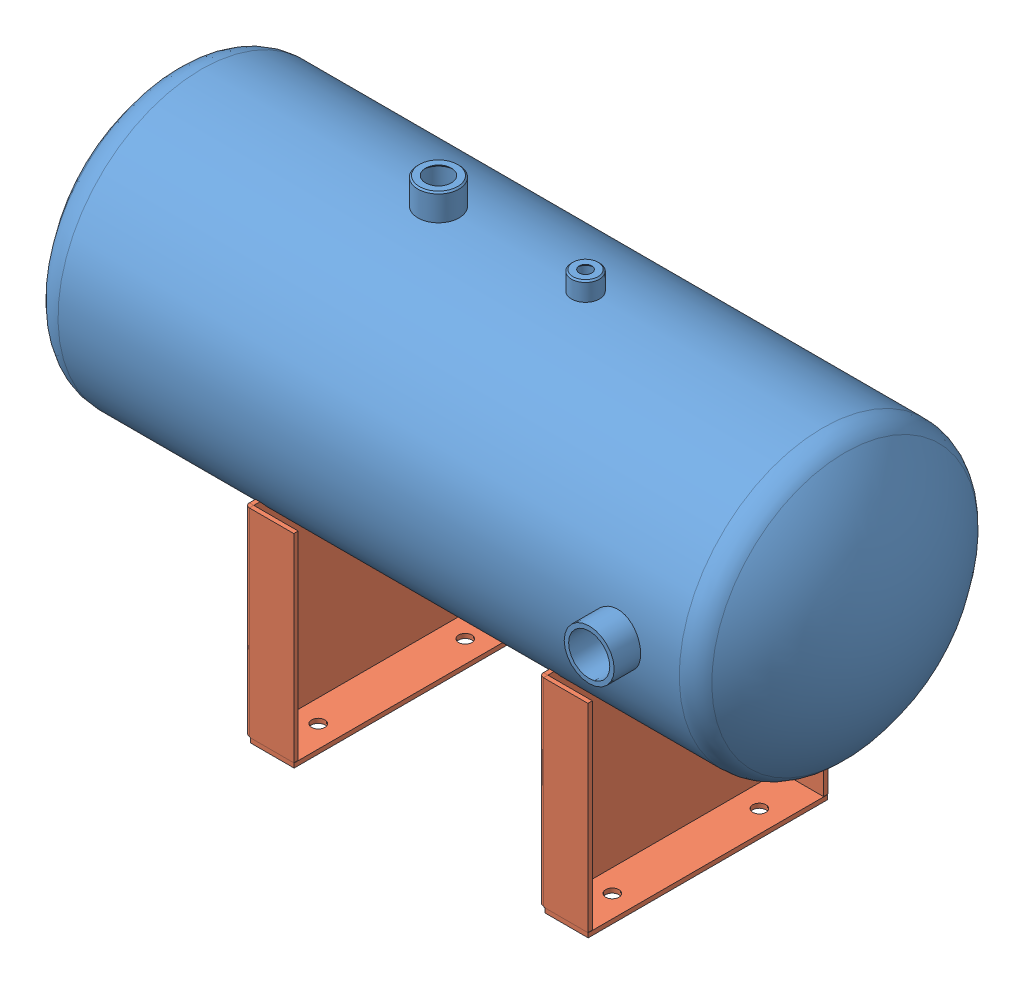
SolidWorks assembly 儲氣桶, configuration 預設. Lengths in mm.
Overall size (520 316.72 213).
3 component instances, 2 part files, 3 mates.
Components (placement in the parent):
- LB-A54A-01-1-1: LB-A54A-01-1 [預設] at (-252.8276 -80.2188 -9) size (520 231 213)
- LB-A54-11-1-1: LB-A54-11-1 [預設] at (107.1711 -193.7188 100.4) x (0 0 -1) z (1 0 0) size (163.24 138.26 33.22)
- LB-A54-11-1-2: LB-A54-11-1 [預設] at (-92.8289 -193.7188 100.4) x (0 0 -1) z (1 0 0) size (163.24 138.26 33.22)
Mates (geometry in assembly coordinates):
- 同軸心1: concentric anti-aligned: cylinder of LB-A54A-01-1-1 through (267.1711 35.2812 -9) axis (1 0 0) radius 97.5; cylinder of LB-A54-11-1-1 through (110.1711 35.2812 -9) axis (-1 0 0) radius 97.5
- 平行1: parallel aligned: plane of LB-A54A-01-1-1 through (7.1711 150.7812 -9) normal (0 1 0); plane of LB-A54-11-1-1 through (109.8911 -162.9388 69.9) normal (0 1 0)
- 平行相距1: distance = 51 mm anti-aligned: plane of LB-A54-11-1-1 through (110.1711 -163.2188 69.9) normal (1 0 0); cylinder of LB-A54A-01-1-1 through (175.1711 -80.2188 -9) axis (0 -1 0) radius 14
